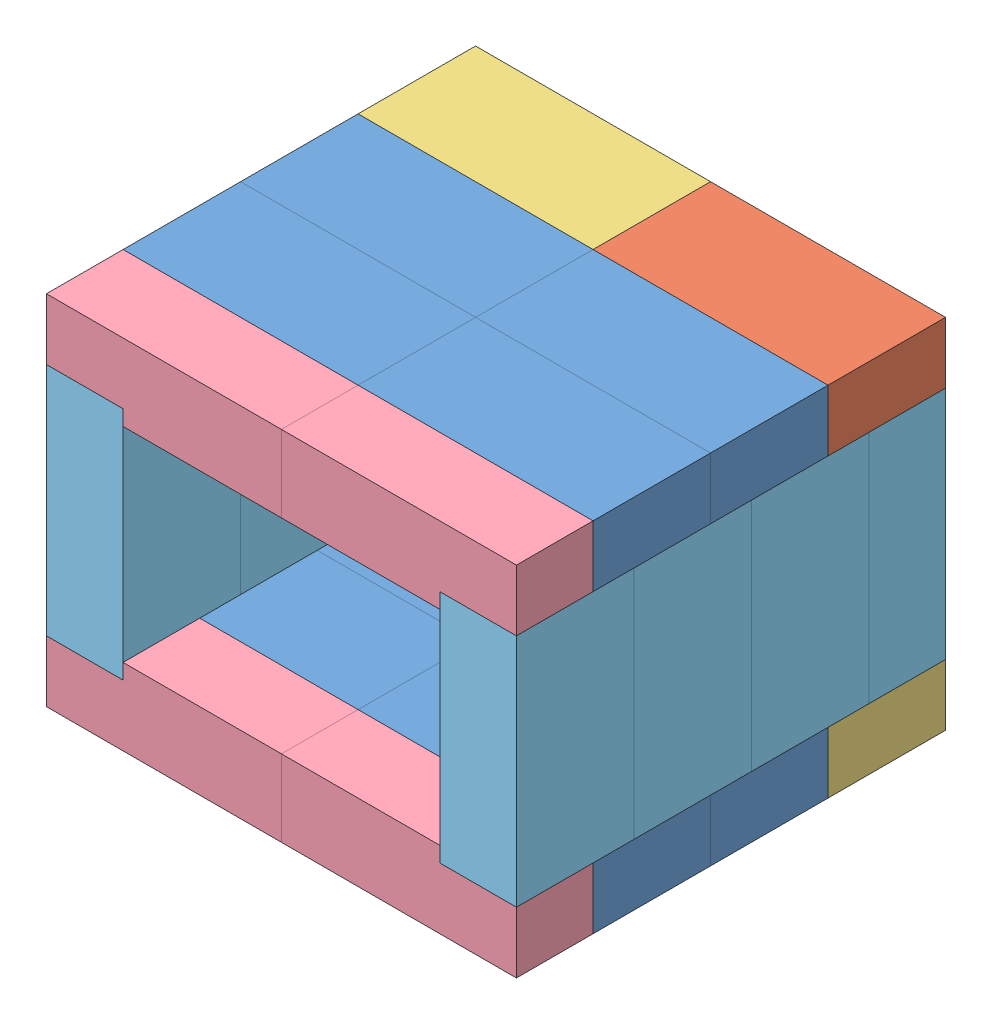
SolidWorks assembly Assem1, configuration Default. Lengths in mm.
Overall size (466.06 350 426.69).
31 component instances, 5 part files, 10 mates.
Components (placement in the parent):
- Heat Treat Asm Top-Bot-1: Heat Treat Asm Top-Bot [Default] at (151.8985 233.2439 368.1674) size (460 75 420)
  - Brick-Sharp-BackCut-1: Brick-Sharp-BackCut [Default] at (63.541 113.2041 192.9534) size (230 75 115)
  - Brick-Sharp-BackRightCut-1: Brick-Sharp-BackRightCut [Default] at (63.541 113.2041 77.9534) size (230 75 115)
  - Brick-Sharp-BackLeftCut-2: Brick-Sharp-BackLeftCut [Default] at (293.541 113.2041 77.9534) x (-1 0 0) z (0 0 -1) size (230 75 115)
  - Brick-Sharp-BackCut-2: Brick-Sharp-BackCut [Default] at (63.541 113.2041 307.9534) size (230 75 115)
  - Brick-Sharp-BackCut-4: Brick-Sharp-BackCut [Default] at (293.541 113.2041 192.9534) x (-1 0 0) z (0 0 -1) size (230 75 115)
  - Brick-Sharp-BackCut-5: Brick-Sharp-BackCut [Default] at (293.541 113.2041 307.9534) x (-1 0 0) z (0 0 -1) size (230 75 115)
  - Brick-Sharp-BackCutTrimmed-1: Brick-Sharp-BackCutTrimmed [Default] at (63.541 113.2041 422.9534) size (230 75 75)
  - Brick-Sharp-BackCutTrimmed-2: Brick-Sharp-BackCutTrimmed [Default] at (293.541 113.2041 382.9534) x (-1 0 0) z (0 0 -1) size (230 75 75)
- Heat Treat Asm Back-2: Heat Treat Asm Back [Default] at (69.1914 358.8149 254.6164) x (0.999924 0.008727 0.008726) z (-0.008727 0 0.999962) size (462.63 234.01 79.01)
  - Brick-Sharp-1: Brick-Sharp [Default] at (91.3299 124.3408 170.7235) x (-0.008727 -0.999962 0) z (-0.999924 0.008726 0.008727) size (230 75 115)
  - Brick-Sharp-2: Brick-Sharp [Default] at (206.3211 123.3373 169.7199) x (0.008727 0.999962 0) z (-0.999924 0.008726 0.008727) size (230 75 115)
  - Brick-Sharp-3: Brick-Sharp [Default] at (436.3036 121.3303 167.7128) x (-0.008727 -0.999962 0) z (0.999924 -0.008726 -0.008727) size (230 75 115)
  - Brick-Sharp-4: Brick-Sharp [Default] at (321.3124 122.3338 168.7164) x (-0.008727 -0.999962 0) z (0.999924 -0.008726 -0.008727) size (230 75 115)
- Heat Treat Asm Side-1: Heat Treat Asm Side [Default] at (351.435 358.8149 839.8689) x (0.008726 0.008727 -0.999924) z (0.999962 0 0.008727) size (347.64 233.01 78.01)
  - Brick-Sharp-1: Brick-Sharp [Default] at (91.3299 124.3408 170.7235) x (-0.008727 -0.999962 0) z (-0.999924 0.008726 0.008727) size (230 75 115)
  - Brick-Sharp-2: Brick-Sharp [Default] at (206.3211 123.3373 169.7199) x (0.008727 0.999962 0) z (-0.999924 0.008726 0.008727) size (230 75 115)
  - Brick-Sharp-4: Brick-Sharp [Default] at (321.3124 122.3338 168.7164) x (-0.008727 -0.999962 0) z (0.999924 -0.008726 -0.008727) size (230 75 115)
- Heat Treat Asm Side-2: Heat Treat Asm Side [Default] at (309.4439 358.8149 432.3728) x (-0.008726 0.008727 0.999924) z (-0.999962 0 -0.008727) size (347.64 233.01 78.01)
  - Brick-Sharp-1: Brick-Sharp [Default] at (91.3299 124.3408 170.7235) x (-0.008727 -0.999962 0) z (-0.999924 0.008726 0.008727) size (230 75 115)
  - Brick-Sharp-2: Brick-Sharp [Default] at (206.3211 123.3373 169.7199) x (0.008727 0.999962 0) z (-0.999924 0.008726 0.008727) size (230 75 115)
  - Brick-Sharp-4: Brick-Sharp [Default] at (321.3124 122.3338 168.7164) x (-0.008727 -0.999962 0) z (0.999924 -0.008726 -0.008727) size (230 75 115)
- Heat Treat Asm Top-Bot-2: Heat Treat Asm Top-Bot [Default] at (508.9805 734.6521 368.1674) x (-1 0 0) z (0 0 1) size (460 75 420)
  - Brick-Sharp-BackCut-1: Brick-Sharp-BackCut [Default] at (63.541 113.2041 192.9534) size (230 75 115)
  - Brick-Sharp-BackRightCut-1: Brick-Sharp-BackRightCut [Default] at (63.541 113.2041 77.9534) size (230 75 115)
  - Brick-Sharp-BackLeftCut-2: Brick-Sharp-BackLeftCut [Default] at (293.541 113.2041 77.9534) x (-1 0 0) z (0 0 -1) size (230 75 115)
  - Brick-Sharp-BackCut-2: Brick-Sharp-BackCut [Default] at (63.541 113.2041 307.9534) size (230 75 115)
  - Brick-Sharp-BackCut-4: Brick-Sharp-BackCut [Default] at (293.541 113.2041 192.9534) x (-1 0 0) z (0 0 -1) size (230 75 115)
  - Brick-Sharp-BackCut-5: Brick-Sharp-BackCut [Default] at (293.541 113.2041 307.9534) x (-1 0 0) z (0 0 -1) size (230 75 115)
  - Brick-Sharp-BackCutTrimmed-1: Brick-Sharp-BackCutTrimmed [Default] at (63.541 113.2041 422.9534) size (230 75 75)
  - Brick-Sharp-BackCutTrimmed-2: Brick-Sharp-BackCutTrimmed [Default] at (293.541 113.2041 382.9534) x (-1 0 0) z (0 0 -1) size (230 75 75)
Mates (geometry in assembly coordinates):
- Coincident2: coincident anti-aligned: line of Heat Treat Asm Top-Bot-1/Brick-Sharp-BackLeftCut-2 through (560.4395 368.948 503.6209) axis (0 0 -1); line of Heat Treat Asm Back-2/Brick-Sharp-3 through (560.4395 368.948 388.6209) axis (0 0 1)
- Coincident3: coincident aligned: line of Heat Treat Asm Top-Bot-1/Brick-Sharp-BackLeftCut-2 through (560.4395 368.948 388.6209) axis (-1 0 0); line of Heat Treat Asm Back-2/Brick-Sharp-3 through (560.4395 368.948 388.6209) axis (-1 0 0)
- Coincident4: coincident anti-aligned: plane of Heat Treat Asm Back-2/Brick-Sharp-3 through (502.9395 483.948 463.6209) normal (0 0 1); plane of Heat Treat Asm Side-1/Brick-Sharp-4 through (485.4395 598.948 463.6209) normal (0 0 -1)
- Coincident5: coincident anti-aligned: line of Heat Treat Asm Top-Bot-1/Brick-Sharp-BackCut-4 through (560.4395 368.948 618.6209) axis (0 0 -1); line of Heat Treat Asm Side-1/Brick-Sharp-2 through (560.4395 368.948 578.6209) axis (0 0 1)
- Coincident6: coincident anti-aligned: plane of Heat Treat Asm Back-2/Brick-Sharp-1 through (157.9395 483.948 463.6209) normal (0 0 1); plane of Heat Treat Asm Side-2/Brick-Sharp-1 through (100.4395 598.948 463.6209) normal (0 0 -1)
- Coincident7: coincident aligned: line of Heat Treat Asm Top-Bot-1/Brick-Sharp-BackCutTrimmed-1 through (175.4395 368.948 808.6209) axis (-1 0 0); line of Heat Treat Asm Side-2/Brick-Sharp-4 through (175.4395 368.948 808.6209) axis (-1 0 0)
- Coincident8: coincident anti-aligned: line of Heat Treat Asm Top-Bot-1/Brick-Sharp-BackCutTrimmed-1 through (100.4395 368.948 733.6209) axis (0 0 1); line of Heat Treat Asm Side-2/Brick-Sharp-4 through (100.4395 368.948 808.6209) axis (0 0 -1)
- Coincident9: coincident: plane of Heat Treat Asm Back-2/Brick-Sharp-1 through (215.4395 598.948 463.6209) normal (0 1 0); plane of Heat Treat Asm Top-Bot-2/Brick-Sharp-BackRightCut-1 through (445.4395 598.948 446.1209) normal (0 -1 0)
- Coincident10: coincident: line of Heat Treat Asm Side-1/Brick-Sharp-1 through (560.4395 598.948 693.6209) axis (0 0 1); line of Heat Treat Asm Top-Bot-2/Brick-Sharp-BackCutTrimmed-1 through (560.4395 598.948 733.6209) axis (0 0 1)
- Coincident11: coincident anti-aligned: line of Heat Treat Asm Side-1/Brick-Sharp-1 through (560.4395 598.948 808.6209) axis (0 -1 0); line of Heat Treat Asm Top-Bot-2/Brick-Sharp-BackCutTrimmed-1 through (560.4395 598.948 808.6209) axis (0 1 0)
